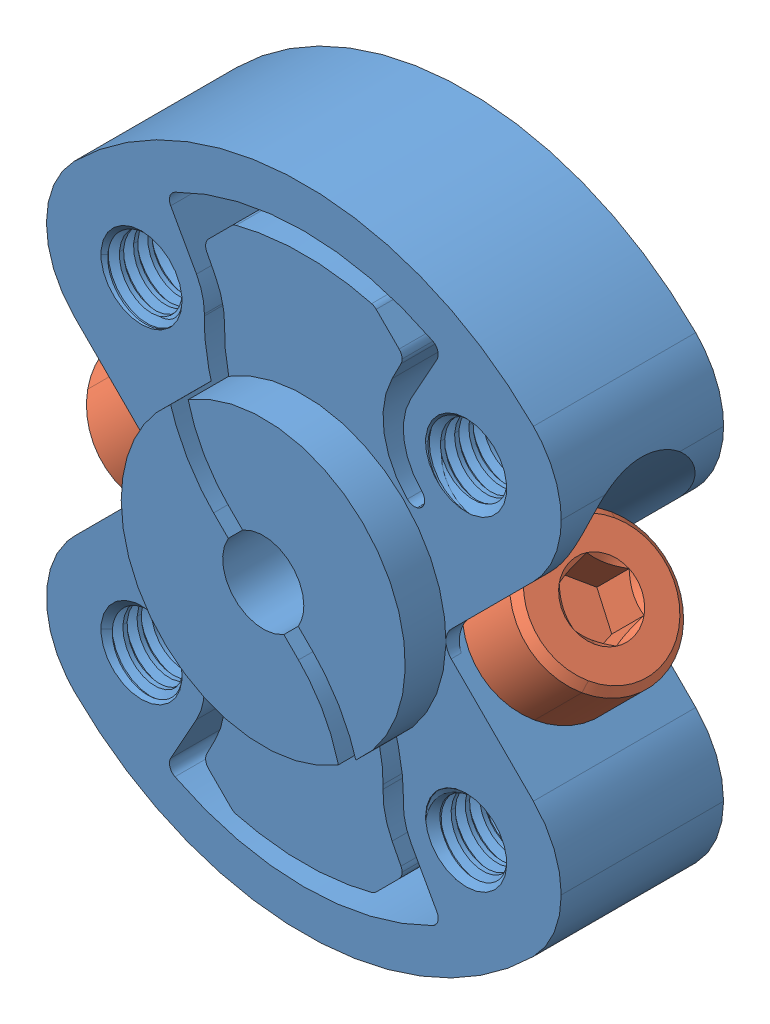
SolidWorks assembly 4mm Hub 1309-0016-0004, configuration Default. Lengths in mm.
Overall size (28.36 32 10.95).
3 component instances, 2 part files, 0 mates.
Components (placement in the parent):
- 1309-0016-0004.STEP-1: 1309-0016-0004.STEP [Default] at (-39.9705 9.0554 14.001) size (25.38 32 10)
- 2800-0004-0014_90128A207.STEP-1: 2800-0004-0014_90128A207.STEP [Default] at (-37.9177 20.1741 14.001) x (0.5 -0.5 -0.707107) z (0.707107 0.707107 0) size (7 7 18.01)
- 2800-0004-0014_90128A207.STEP-2: 2800-0004-0014_90128A207.STEP [Default] at (-42.0234 -2.0634 14.001) x (-0.5 0.5 -0.707107) z (-0.707107 -0.707107 0) size (7 7 18.01)
